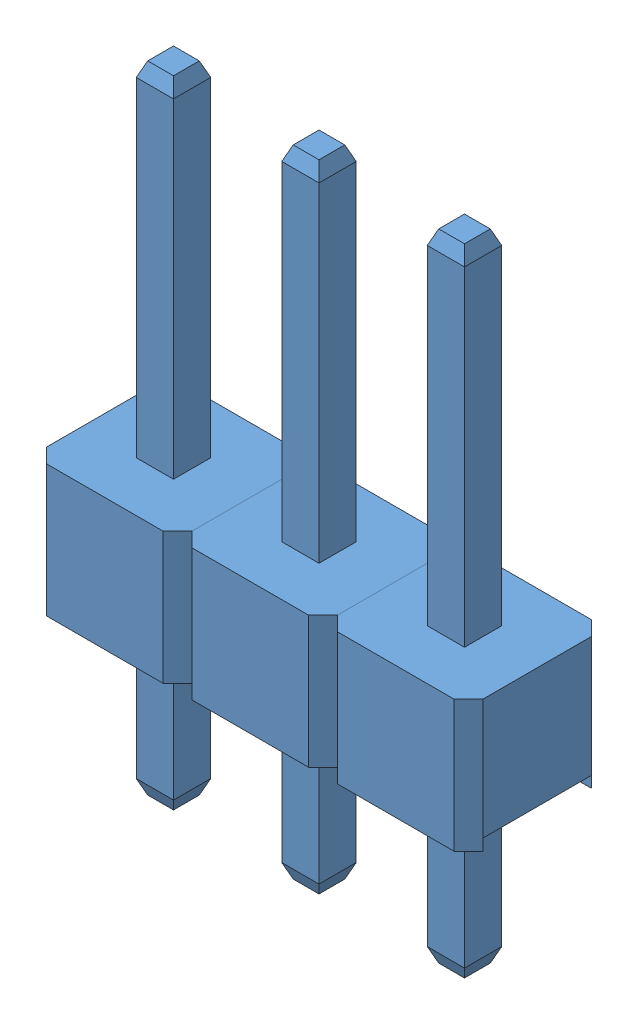
SolidWorks assembly 3x_Male_Pin_2.54_mm.STEP, configuration Default. Lengths in mm.
Overall size (7.62 11.1 2.4).
3 component instances, 1 part files, 0 mates.
Components (placement in the parent):
- 1_Male_Pin_2.54_mm.STEP-1: 1_Male_Pin_2.54_mm.STEP [Default] at (3.8763 2.2562 11.0637) size (2.54 11.1 2.4)
- 1_Male_Pin_2.54_mm.STEP-2: 1_Male_Pin_2.54_mm.STEP [Default] at (1.3363 2.2562 11.0637) size (2.54 11.1 2.4)
- 1_Male_Pin_2.54_mm.STEP-3: 1_Male_Pin_2.54_mm.STEP [Default] at (-1.2037 2.2562 11.0637) size (2.54 11.1 2.4)
